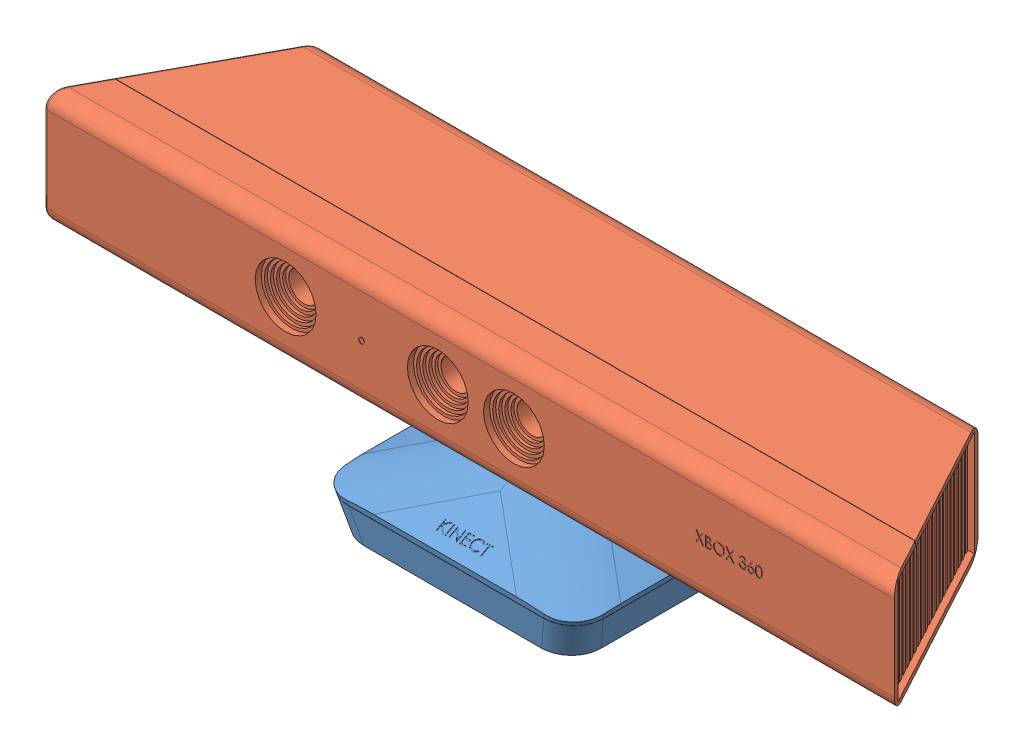
SolidWorks assembly final kinect, configuration Default. Lengths in mm.
Overall size (279.32 72.5 71.02).
2 component instances, 2 part files, 2 mates.
Components (placement in the parent):
- lower part-1: lower part [Default] at (2.1296 -16.1755 0.9636) size (86.05 27.21 71.02)
- kinect upper part-1: kinect upper part [Default] at (2.268 17.8245 -1.5083) size (279.32 60 60)
Mates (geometry in assembly coordinates):
- Concentric1: concentric: sphere of lower part-1; sphere of kinect upper part-1
- Parallel1: parallel anti-aligned: plane of lower part-1 through (-26.5143 -16.6755 23.2804) normal (0 -1 0); plane of kinect upper part-1 through (2.268 55.8245 -1.5083) normal (0 1 0)
